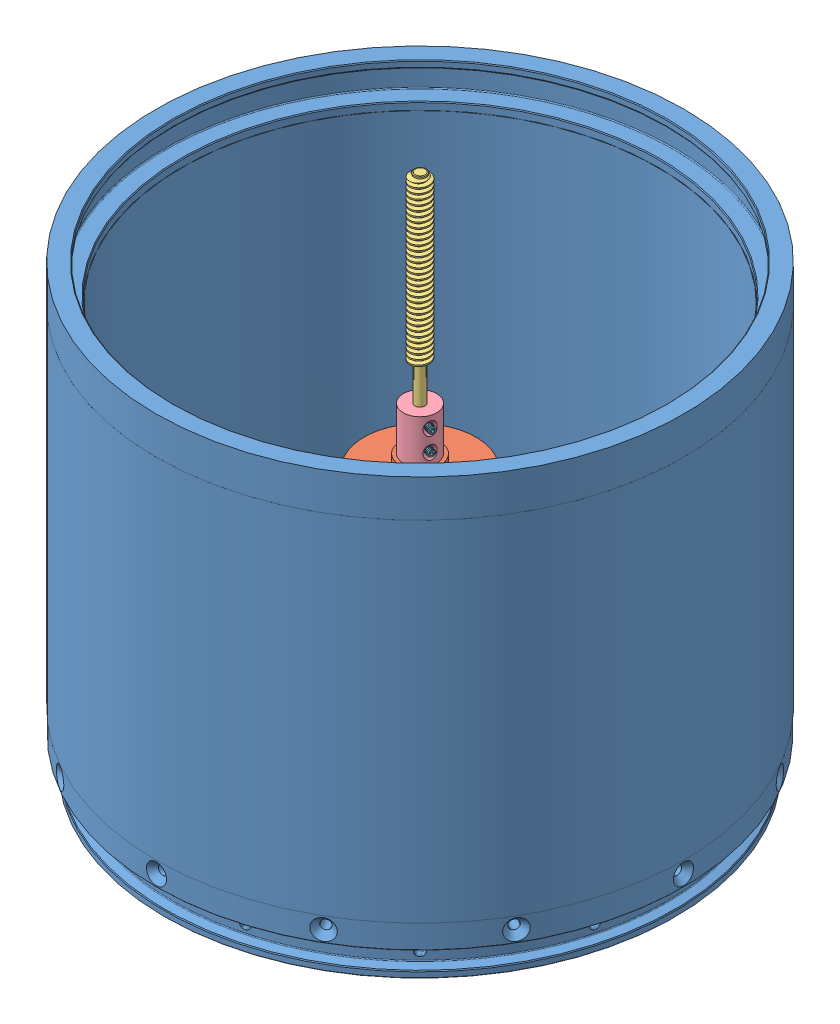
SolidWorks assembly Lower_Ring_REF_Assem, configuration Default. Lengths in mm.
Overall size (169.16 166.19 169.16).
7 component instances, 5 part files, 6 mates.
Components (placement in the parent):
- Lower_Ring-1: Lower_Ring [Default] at (-22.0591 -19.4905 1.2981) size (169.16 141.12 169.16)
- Motor1_small-1: Motor1_small [Default] at (-22.0591 28.0936 1.2981) x (0 1 0) z (0.475154 0 0.879902) size (67.95 37.34 37.34)
- ACME_Screw-1: ACME_Screw [Default] at (-22.0591 66.2345 1.2981) x (0 -1 0) z (0 0 1) size (70.01 6.35 6.51)
- 0.125_0.5_Coupler-1: 0.125_0.5_Coupler [Default] at (-20.3654 55.2004 -13.8829) x (0.950754 0 0.309947) z (-0.309947 0 0.950754) size (11.98 13.97 10.67)
  - 0.125_0.5_Coupler-1: 0.125_0.5_Coupler [Default] at (3.095 2.7029 14.9583) size (10.67 13.97 10.67)
  - 97705A142-1: 97705A142 [97705A142] at (7.3322 12.9938 14.9389) x (-0.004504 -0.175182 -0.984526) z (0.99999 0 -0.004574) size (2.52 2.21 4.96)
  - 97705A142-2: 97705A142 [97705A142] at (6.8507 6.382 14.9411) x (-0.000926 -0.979309 -0.202367) z (0.99999 0 -0.004574) size (2.52 2.21 4.96)
Mates (geometry in assembly coordinates):
- Concentric1: concentric: cylinder of Lower_Ring-1 through (-22.0591 18.6095 1.2981) axis (0 -1 0) radius 25.4; cylinder of Motor1_small-1 through (-22.0591 -9.5452 1.2981) axis (0 -1 0) radius 17.907
- Coincident4: coincident: plane of Lower_Ring-1 through (-22.0591 -1.7105 1.2981) normal (0 1 0); plane of Motor1_small-1 through (-22.0591 -1.7105 1.2981) normal (0 -1 0)
- Concentric2: concentric: cylinder of Motor1_small-1 through (-22.0591 -9.5452 1.2981) axis (0 -1 0) radius 1.5875; cylinder of 0.125_0.5_Coupler-1/0.125_0.5_Coupler-1 through (-22.0591 71.8733 1.2981) axis (0 -1 0) radius 1.5875
- Coincident5: coincident: plane of Motor1_small-1 through (-27.7582 57.9033 4.3757) normal (0 1 0); plane of 0.125_0.5_Coupler-1/0.125_0.5_Coupler-1 through (-22.0591 57.9033 1.2981) normal (0 -1 0)
- Coincident6: coincident: plane of Motor1_small-1 through (-23.4559 66.2345 2.0524) normal (0 1 0); plane of ACME_Screw-1 through (-18.8841 66.2345 1.2981) normal (0 -1 0)
- Concentric3: concentric: cylinder of ACME_Screw-1 through (-22.0591 53.5088 1.2981) axis (0 -1 0) radius 1.5875; cylinder of 0.125_0.5_Coupler-1/0.125_0.5_Coupler-1 through (-22.0591 71.8733 1.2981) axis (0 -1 0) radius 1.5875
